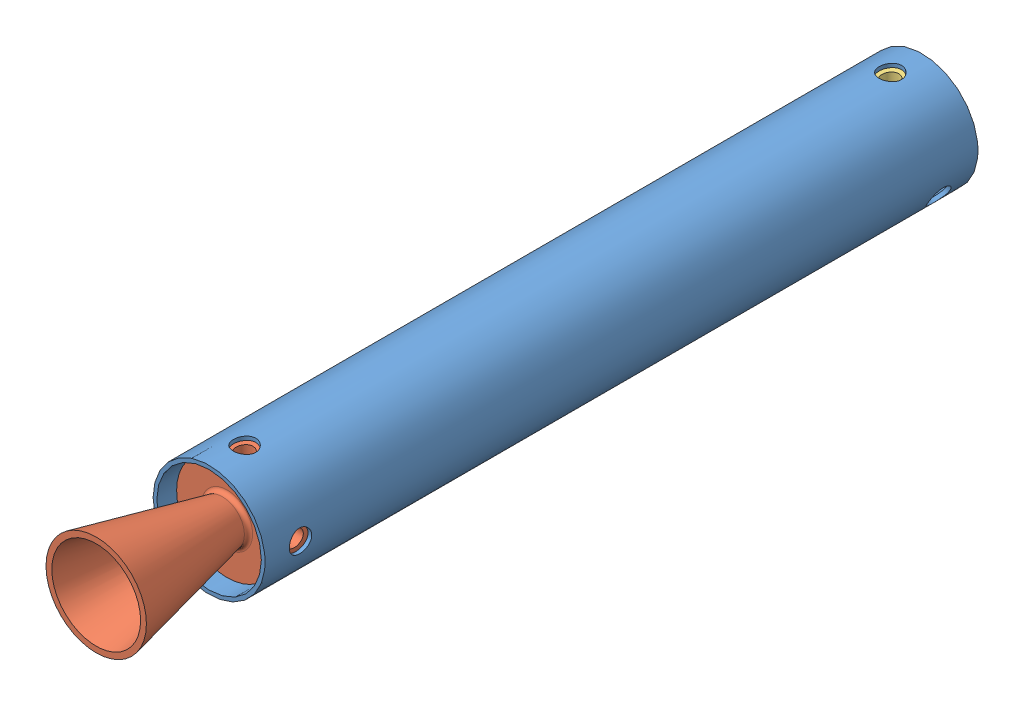
SolidWorks assembly Assemblage, configuration Défaut. Lengths in mm.
Overall size (30 30 221.25).
3 component instances, 3 part files, 4 mates.
Components (placement in the parent):
- Chambre-1: Chambre [Défaut] at (-2.749 1.3745 95.5) size (30 30 191)
- Tuyère-1: Tuyère [Défaut] at (-2.749 1.3745 276.5215) x (-0.001411 -0.999999 0) z (0.999999 -0.001411 0) size (27 56.25 27)
- Cloison-1: Cloison [Défaut] at (-2.749 1.3745 113.3) x (1 0 0) z (0 1 0) size (26.9 13 26.9)
Mates (geometry in assembly coordinates):
- Coaxiale3: concentric anti-aligned: cylinder of Chambre-1 through (-2.749 1.3745 259.5) axis (0 0 1) radius 14; cylinder of Tuyère-1 through (-2.749 1.3745 245.4519) axis (0 0 -1) radius 13.5
- Coaxiale7: concentric anti-aligned: cylinder of Chambre-1 through (-2.749 -13.6265 277) axis (0 1 0) radius 3; cylinder of Tuyère-1 through (-2.749 -12.1255 277) axis (0 -1 0) radius 2.25
- Coaxiale8: concentric aligned: cylinder of Chambre-1 through (-2.749 1.3745 114.5) axis (0 0 -1) radius 14; cylinder of Cloison-1 through (-2.749 1.3745 109.8) axis (0 0 -1) radius 13.45
- Coaxiale9: concentric anti-aligned: cylinder of Chambre-1 through (-20.4953 -8.8714 104) axis (0.866025 0.5 0) radius 3; cylinder of Cloison-1 through (-14.397 -5.3505 104) axis (-0.866025 -0.5 0) radius 2.25
